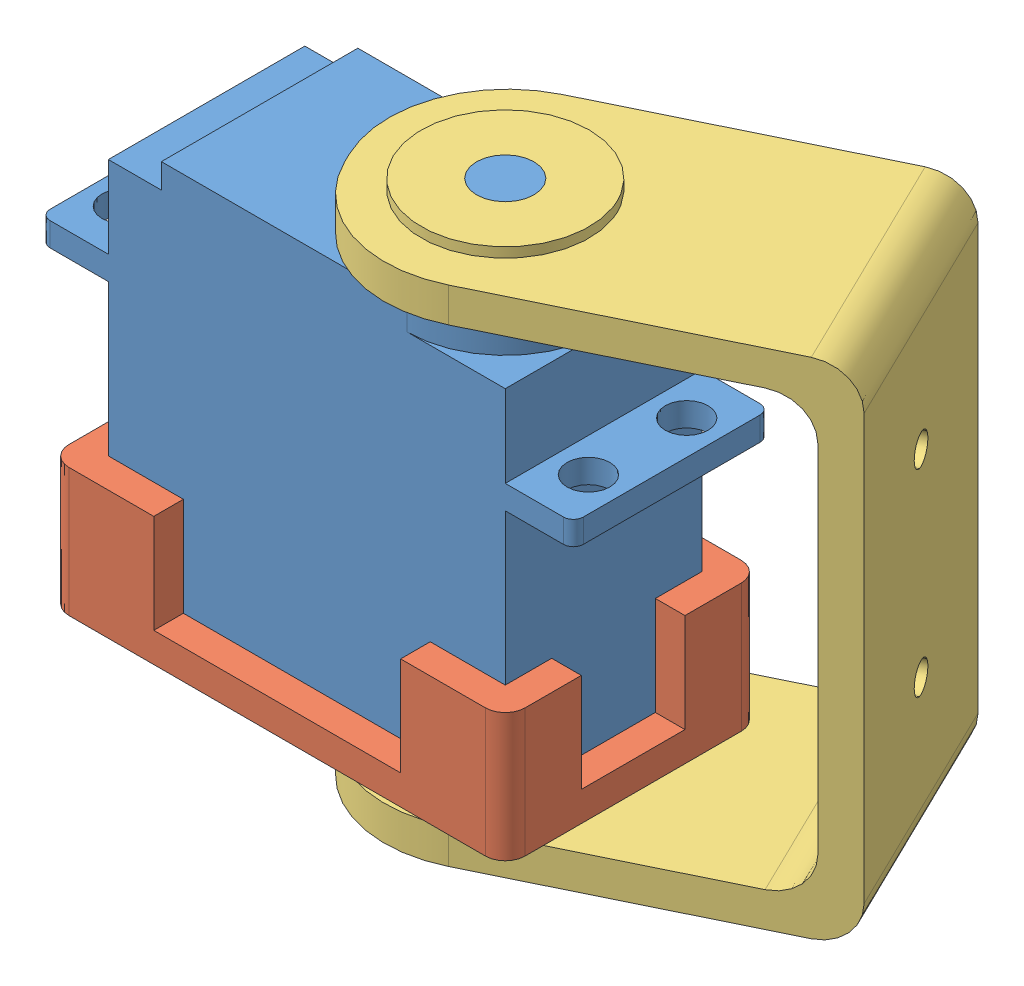
SolidWorks assembly Ensamblaje1, configuration Predeterminado. Lengths in mm.
Overall size (70.94 52.5 41.52).
3 component instances, 3 part files, 6 mates.
Components (placement in the parent):
- Servo-1: Servo [Predeterminado] at (1.1253 -26.6032 54) size (54 44.5 19.9)
- Pieza1-1: Pieza1 [Predeterminado] at (1.1253 -16.6032 54) x (0 0 -1) z (-1 0 0) size (25.9 18 46.2)
- Pieza2-1: Pieza2 [Predeterminado] at (41.922 -8.6032 52.9837) x (0 1 0) z (-0.899125 0 0.437692) size (52 25 43.5)
Mates (geometry in assembly coordinates):
- Coincidente1: coincident anti-aligned: plane of Servo-1 through (-18.9747 9.3968 44.05) normal (-1 0 0); plane of Pieza1-1 through (-18.9747 -26.6032 63.95) normal (1 0 0)
- Coincidente2: coincident anti-aligned: plane of Servo-1 through (1.1253 -26.6032 54) normal (0 -1 0); plane of Pieza1-1 through (1.1253 -26.6032 54) normal (0 1 0)
- Coincidente3: coincident anti-aligned: plane of Servo-1 through (-18.9747 9.3968 44.05) normal (0 0 -1); plane of Pieza1-1 through (21.2253 -26.6032 44.05) normal (0 0 1)
- Concéntrica1: concentric anti-aligned: cylinder of Pieza1-1 through (11.2753 -34.6032 54) axis (0 1 0) radius 7.5; cylinder of Pieza2-1 through (11.2753 -24.1032 54) axis (0 -1 0) radius 7.75
- Paralelo1: parallel anti-aligned: cylinder of Servo-1 through (11.2753 17.8968 54) axis (0 -1 0) radius 2.91; cylinder of Pieza2-1 through (11.2753 6.8968 54) axis (0 1 0) radius 2.8
- Coincidente4: coincident anti-aligned: plane of Pieza1-1 through (11.2753 -30.6032 54) normal (0 -1 0); plane of Pieza2-1 through (30.9797 -30.6032 30.5056) normal (0 1 0)
